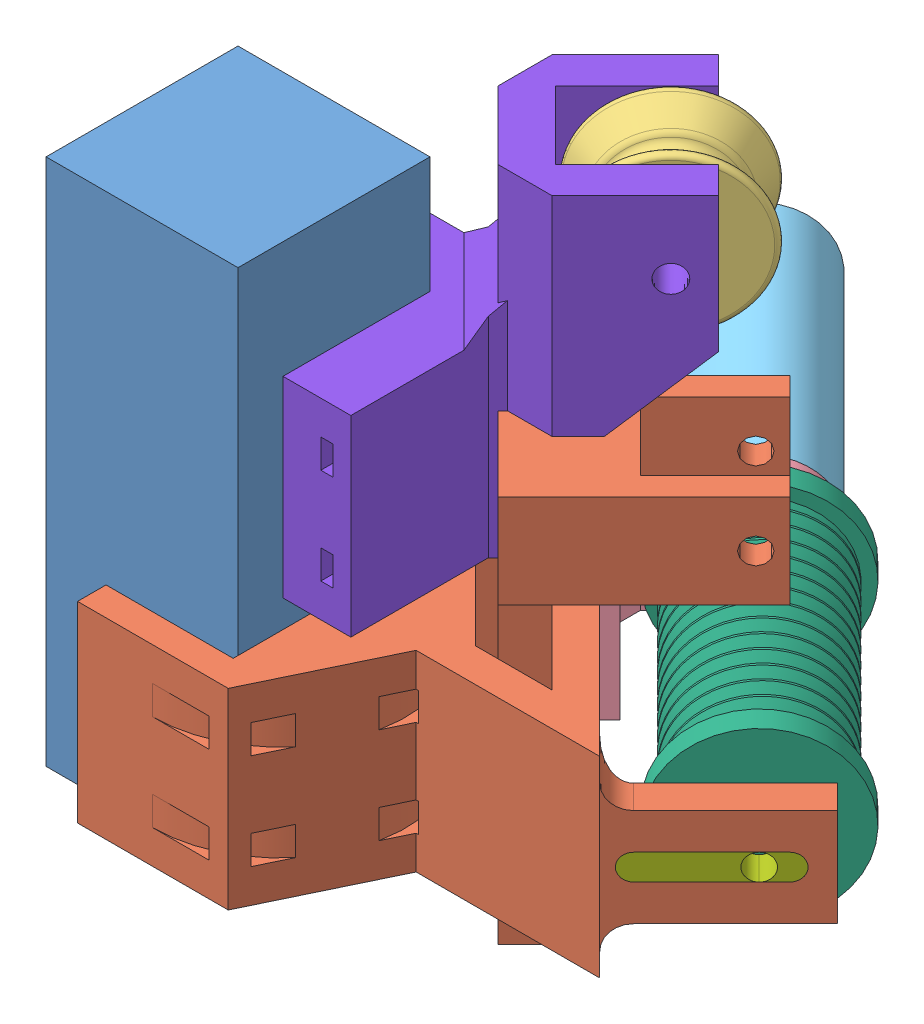
SolidWorks assembly imprvedMechanism, configuration Default. Lengths in mm.
Overall size (306.23 128.41 265.8).
8 component instances, 8 part files, 14 mates.
Components (placement in the parent):
- tableLeg-1: tableLeg [Default] at (50.0377 26.8176 100.477) size (40 110 40)
- square With wire directionalSmaller SecondSupport-1: square With wire directionalSmaller SecondSupport [Default] at (43.5377 46.8176 100.977) size (298.83 105.47 258.03)
- Improvedpulley-1: Improvedpulley [Default] at (89.0533 127.5281 49.3087) x (0.707107 0 0.707107) z (-0.443688 0.778641 0.443688) size (18 32.63 32.63)
- braket-1: braket [Default] at (73.443 44.8547 48.5147) x (0.707107 0 0.707107) z (0 1 0) size (34 36.5 26)
- DC MOTOR-1: DC MOTOR [Default] at (33.1379 44.8547 -25.0244) x (0.5 -0.707107 -0.5) z (-0.5 -0.707107 0.5) size (25 76 25)
- threaded_cable_retractor-1: threaded_cable_retractor [Default] at (72.5744 44.8547 14.412) x (-0.65509 -0.37645 0.65509) z (-0.266191 0.926437 0.266191) size (35 148 35)
- keyForHolder-1: keyForHolder [Default] at (124.4911 46.8176 92.4917) x (0 -1 0) z (-0.707107 0 0.707107) size (5.4 7 28.4)
- pulleySupport-1: pulleySupport [Default] at (145.0377 112.5281 5.477) size (83.77 70 83.77)
Mates (geometry in assembly coordinates):
- Coincident1: coincident anti-aligned: plane of tableLeg-1 through (30.0377 136.8176 80.477) normal (0 0 -1); plane of square With wire directionalSmaller SecondSupport-1 through (70.0377 16.8176 80.477) normal (0 0 1)
- Coincident2: coincident anti-aligned: plane of tableLeg-1 through (70.0377 136.8176 80.477) normal (1 0 0); plane of square With wire directionalSmaller SecondSupport-1 through (70.0377 16.8176 80.477) normal (-1 0 0)
- Coincident3: coincident aligned: plane of tableLeg-1 through (50.0377 26.8176 100.477) normal (0 -1 0); plane of square With wire directionalSmaller SecondSupport-1 through (43.5377 26.8176 100.977) normal (0 -1 0)
- Coincident4: coincident anti-aligned: plane of square With wire directionalSmaller SecondSupport-1 through (125.9053 26.8176 100.977) normal (0.707107 0 -0.707107); plane of braket-1 through (73.443 44.8547 48.5147) normal (-0.707107 0 0.707107)
- Parallel1: parallel aligned: plane of square With wire directionalSmaller SecondSupport-1 through (43.5377 26.8176 100.977) normal (0 -1 0); plane of braket-1 through (64.6042 31.8547 35.4332) normal (0 -1 0)
- Coincident6: coincident anti-aligned: plane of braket-1 through (64.6042 31.8547 35.4332) normal (-0.707107 0 -0.707107); plane of DC MOTOR-1 through (79.0999 44.8547 20.9376) normal (0.707107 0 0.707107)
- Concentric2: concentric aligned: cylinder of braket-1 through (102.788 44.8547 44.6256) axis (-0.707107 0 -0.707107) radius 4; cylinder of DC MOTOR-1 through (86.8781 44.8547 28.7157) axis (-0.707107 0 -0.707107) radius 2
- Concentric3: concentric aligned: cylinder of DC MOTOR-1 through (86.8781 44.8547 28.7157) axis (-0.707107 0 -0.707107) radius 2; cylinder of threaded_cable_retractor-1 through (85.3023 44.8547 27.14) axis (-0.707107 0 -0.707107) radius 10
- Concentric4: concentric anti-aligned: cylinder of square With wire directionalSmaller SecondSupport-1 through (115.2987 46.8176 83.2993) axis (0.707107 0 0.707107) radius 2.7; cylinder of keyForHolder-1 through (129.4408 46.8176 97.4414) axis (-0.707107 0 -0.707107) radius 2.7
- Coincident7: coincident anti-aligned: plane of square With wire directionalSmaller SecondSupport-1 through (115.2987 44.1176 83.2993) normal (0 1 0); plane of keyForHolder-1 through (129.4408 44.1176 97.4414) normal (0 -1 0)
- Coincident8: coincident aligned: plane of square With wire directionalSmaller SecondSupport-1 through (150.654 57.0269 76.2282) normal (0.707107 0 0.707107); plane of keyForHolder-1 through (129.4408 46.8176 97.4414) normal (0.707107 0 0.707107)
- Coincident9: coincident anti-aligned: plane of tableLeg-1 through (30.0377 136.8176 80.477) normal (0 0 -1); plane of pulleySupport-1 through (70.0377 72.5281 80.477) normal (0 0 1)
- Coincident10: coincident anti-aligned: plane of tableLeg-1 through (70.0377 136.8176 80.477) normal (1 0 0); plane of pulleySupport-1 through (70.0377 72.5281 111.1096) normal (-1 0 0)
- Concentric9: concentric aligned: cylinder of Improvedpulley-1 through (89.0533 127.5281 49.3087) axis (0.707107 0 0.707107) radius 2.7; cylinder of pulleySupport-1 through (61.8956 127.5281 22.1511) axis (0.707107 0 0.707107) radius 2.8
